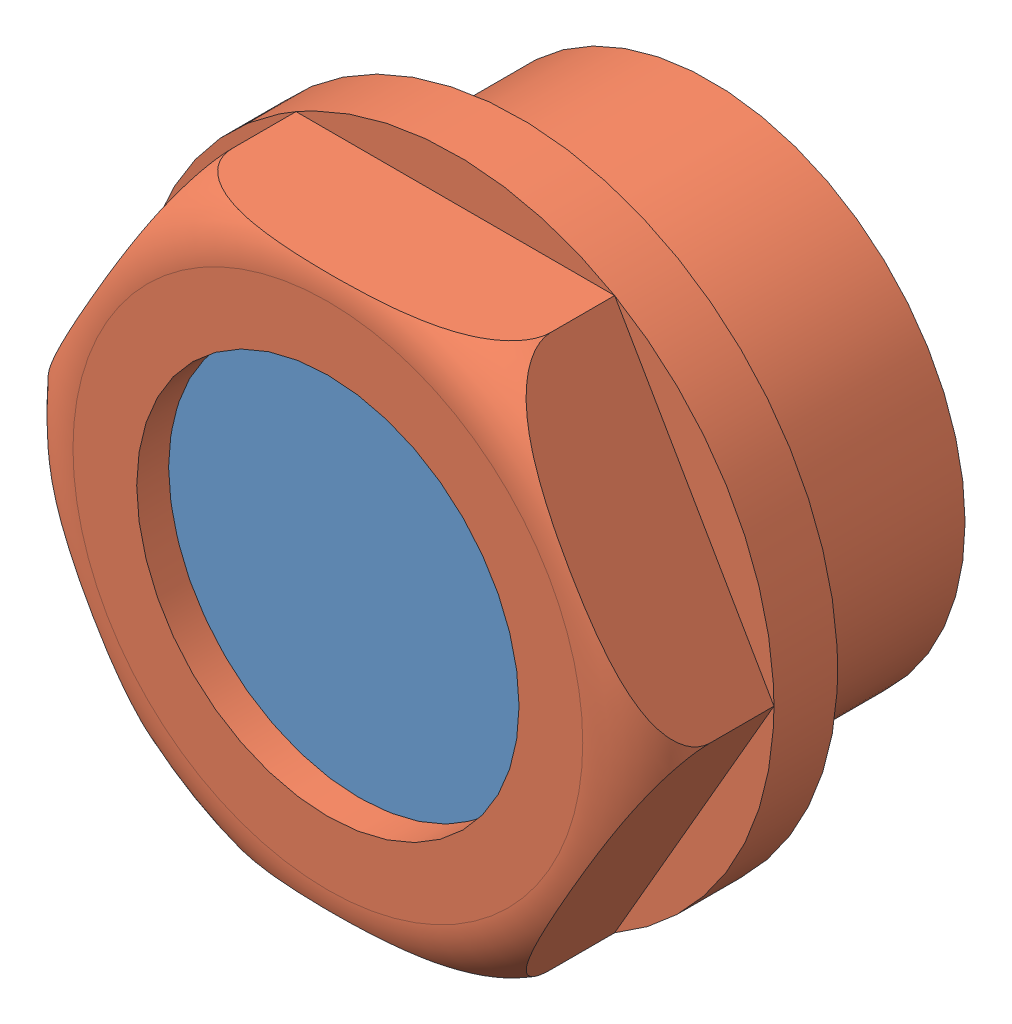
SolidWorks assembly A34, configuration 默认. Lengths in mm.
Overall size (20 20 12).
2 component instances, 2 part files, 2 mates.
Components (placement in the parent):
- A34-2-1: A34-2 [默认] at (-2.3761 -0.4001 0) size (12 12 2)
- A34-1-1: A34-1 [默认] at (-2.3761 -0.4001 -9) size (21 20 12.37)
Mates (geometry in assembly coordinates):
- 同心1: concentric aligned: cylinder of A34-2-1 through (-2.3761 -0.4001 2) axis (0 0 -1) radius 6; cylinder of A34-1-1 through (-2.3761 -0.4001 3) axis (0 0 -1) radius 6
- 距离1: distance = 1 mm aligned: plane of A34-2-1 through (-2.3761 -0.4001 2) normal (0 0 1); plane of A34-1-1 through (-2.3761 -0.4001 3) normal (0 0 1)
